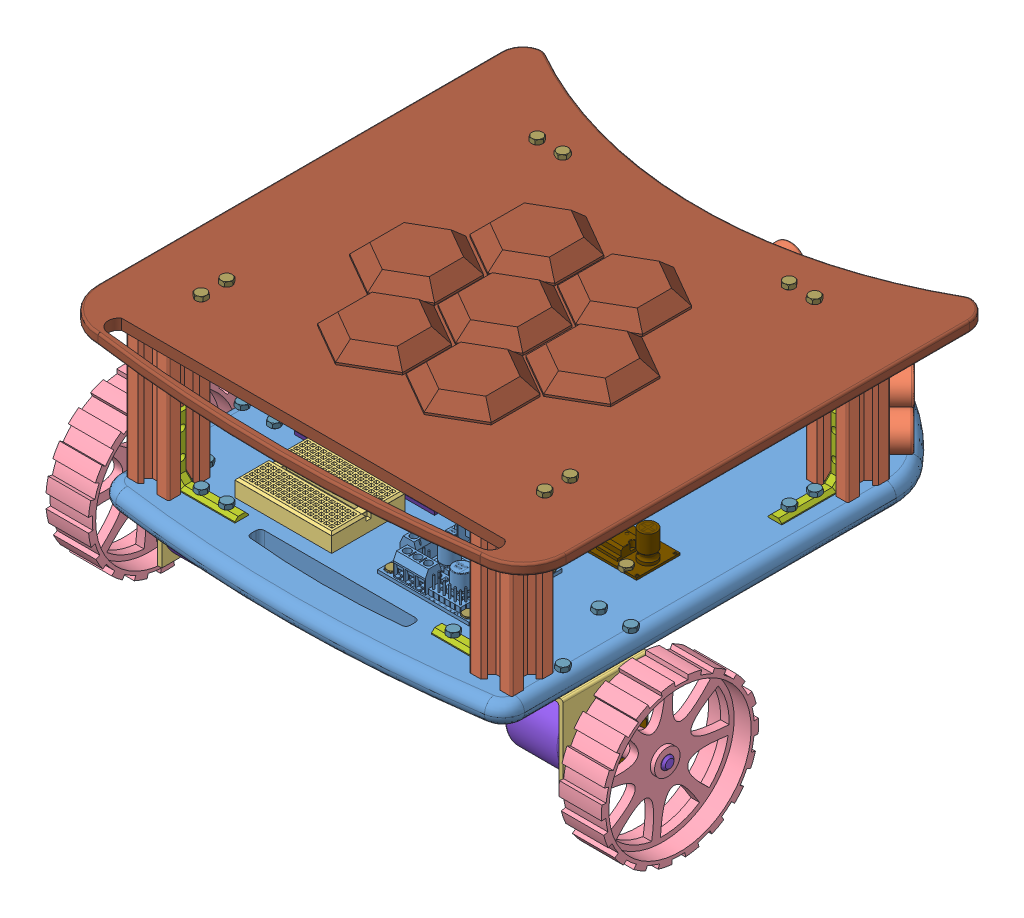
SolidWorks assembly Final_assemb, configuration Default. Lengths in mm.
Overall size (260.12 153.89 257.15).
106 component instances, 21 part files, 114 mates.
Components (placement in the parent):
- Base-1: Base [Default] at (68.6888 135.2882 259.6068) size (190.39 10 252.17)
- aluminium profile-4: aluminium profile [Default] at (-11.2641 145.2882 319.0712) size (20 60 20)
- aluminium profile-5: aluminium profile [Default] at (-12.0261 145.2882 160.7088) size (20 60 20)
- aluminium profile-6: aluminium profile [Default] at (149.3096 145.2882 318.1148) size (20 60 20)
- aluminium profile-7: aluminium profile [Default] at (149.3897 145.2882 159.9163) size (20 60 20)
- motor_mount-1: motor_mount [Default] at (-26.6342 116.2882 288.9148) x (-0.000001 0 -1) z (1 0 -0.000001) size (40 40 23)
- motor_mount-3: motor_mount [Default] at (163.7533 116.2882 288.4009) x (0 0 1) z (-1 0 0) size (40 40 23)
- wheel-1: wheel [Default] at (188.5877 115.3205 288.1355) x (0 0.778001 0.628264) z (-1 0 0) size (73.72 74 22)
- caster wheel.STEP-2: caster wheel.STEP [Default] at (69.4401 93.2882 114.6731) x (-1 0 0) z (0 0 1) size (47 18.41 32)
  - Wheel''s Body.STEP-1: Wheel''s Body.STEP [Default] at origin size (47 8.6 32)
  - Ball.STEP-1: Ball.STEP [Default] at (0 8.6 0) x (0.870425 -0.365315 -0.330008) z (0.347375 -0.019238 0.937529) size (14 14 14)
- L-Bracket-1: L-Bracket [Default] at (-15.1969 145.2882 165.2088) x (0 -1 0) z (1 0 0) size (30 30 6.4)
- L-Bracket-2: L-Bracket [Default] at (146.3725 145.2882 164.4163) x (0 -1 0) z (1 0 0) size (30 30 6.4)
- L-Bracket-4: L-Bracket [Default] at (-6.7641 145.2882 315.9945) x (-1 0 0) z (0 0 1) size (30 30 6.4)
- L-Bracket-5: L-Bracket [Default] at (144.8096 145.2882 321.373) x (1 0 0) z (0 0 -1) size (30 30 6.4)
- dc_motor-1: dc_motor [Default] at (-60.8289 75.9831 269.4134) x (0 0.786629 -0.617426) z (1 0 -0.000001) size (40 40 81)
- dc_motor-2: dc_motor [Default] at (197.948 90.2022 252.8429) x (0 -0.509451 0.8605) z (-1 0 0) size (40 40 81)
- Nut-1: Nut [Default] at (-61.8289 74.5197 307.0863) x (-0.000001 0 -1) z (1 0 -0.000001) size (25.4 22 8)
- Nut-2: Nut [Default] at (136.5586 75.5781 305.943) x (0 0 -1) z (1 0 0) size (25.4 22 8)
- wheel-3: wheel [Default] at (-51.5365 114.3396 289.6726) x (-0.000001 0.009349 -0.999956) z (1 0 -0.000001) size (73.72 74 22)
- castor_support-1: castor_support [Default] at (69.4434 135.2882 114.5913) x (1 0 0) z (0 -1 0) size (54.97 14.97 42)
- L-Bracket-8: L-Bracket [Default] at (-14.8578 205.2882 314.5712) x (0 1 0) z (1 0 0) size (30 30 6.4)
- L-Bracket-9: L-Bracket [Default] at (146.0004 205.2882 313.6148) x (0 1 0) z (1 0 0) size (30 30 6.4)
- L-Bracket-10: L-Bracket [Default] at (-7.5261 205.2882 157.2434) x (0 1 0) z (0 0 1) size (30 30 6.4)
- L-Bracket-11: L-Bracket [Default] at (144.8897 205.2882 156.8646) size (30 30 6.4)
- top plate-4: top plate [Default] at (106.9976 210.2882 168.2291) x (-1 0 0) z (0 -1 0) size (220.27 226.12 12)
- Bolt_assem-2: Bolt_assem [Default] at (121.8897 211.4132 160.0646) x (0.65455 0 0.756019) z (0 -1 0) size (6.35 5 13.28)
- Bolt_assem-3: Bolt_assem [Default] at (15.6675 211.4132 160.4434) x (0.759249 0 -0.650801) z (0 -1 0) size (6.35 5 13.28)
- Bolt_assem-4: Bolt_assem [Default] at (149.2004 211.4132 290.4211) x (1 0 0) z (0 -1 0) size (6.35 5 13.28)
- Bolt_assem-5: Bolt_assem [Default] at (-11.6578 211.4132 303.3776) x (0.046761 0 -0.998906) z (0 -1 0) size (6.35 5 13.28)
- Bolt_assem-6: Bolt_assem [Default] at (-11.6578 211.4132 291.3776) x (1 0 0) z (0 -1 0) size (6.35 5 13.28)
- Bolt_assem-7: Bolt_assem [Default] at (149.2004 211.4132 302.4211) x (1 0 0) z (0 -1 0) size (6.35 5 13.28)
- Bolt_assem-8: Bolt_assem [Default] at (3.6675 211.5814 160.4434) x (1 0 0) z (0 -1 0) size (6.35 5 13.28)
- Bolt_assem-9: Bolt_assem [Default] at (133.8897 211.4132 160.0646) x (1 0 0) z (0 -1 0) size (6.35 5 13.28)
- Nut_assem-1: Nut_assem [Default] at (3.5037 202.2882 160.0608) x (0 0 1) z (0 1 0) size (6.35 5 2.32)
- Nut_assem-2: Nut_assem [Default] at (149.6084 202.2882 290.2996) x (0 0 1) z (0 1 0) size (6.35 5 2.32)
- Nut_assem-3: Nut_assem [Default] at (-11.411 202.2882 291.3133) x (-0.999814 0 -0.019286) z (0 1 0) size (6.35 5 2.32)
- Nut_assem-4: Nut_assem [Default] at (121.6601 202.2882 159.3487) x (0 0 1) z (0 1 0) size (6.35 5 2.32)
- Nut_assem-5: Nut_assem [Default] at (149.4553 202.2882 302.2925) x (0 0 1) z (0 1 0) size (6.35 5 2.32)
- Nut_assem-6: Nut_assem [Default] at (133.8993 202.2882 160.3544) x (0 0 1) z (0 1 0) size (6.35 5 2.32)
- Nut_assem-7: Nut_assem [Default] at (15.634 202.2882 160.571) x (0 0 1) z (0 1 0) size (6.35 5 2.32)
- Nut_assem-8: Nut_assem [Default] at (-12.522 202.2882 303.4842) x (0 0 1) z (0 1 0) size (6.35 5 2.32)
- Bolt_assem_long-1: Bolt_assem_long [Default] at (149.5725 148.4132 187.6099) x (0.999999 0 0.001045) z (0 -1 0) size (6.35 5 17.3)
- Bolt_assem_long-6: Bolt_assem_long [Default] at (149.5725 148.4132 175.6099) x (0.837169 0 -0.546944) z (0 -1 0) size (6.35 5 17.3)
- Bolt_assem_long-7: Bolt_assem_long [Default] at (-11.9969 148.4132 188.4025) x (1 0 0) z (0 -1 0) size (6.35 5 17.3)
- Bolt_assem_long-8: Bolt_assem_long [Default] at (-11.9969 148.4132 176.4025) x (0.837169 0 -0.546944) z (0 -1 0) size (6.35 5 17.3)
- Bolt_assem_long-9: Bolt_assem_long [Default] at (16.2359 148.4132 319.1945) x (1 0 0) z (0 -1 0) size (6.35 5 17.3)
- Bolt_assem_long-10: Bolt_assem_long [Default] at (4.2359 148.4132 319.1945) x (1 0 0) z (0 -1 0) size (6.35 5 17.3)
- Bolt_assem_long-11: Bolt_assem_long [Default] at (121.8096 148.4132 318.173) x (1 0 0) z (0 -1 0) size (6.35 5 17.3)
- Bolt_assem_long-12: Bolt_assem_long [Default] at (133.8096 148.4132 318.173) x (1 0 0) z (0 -1 0) size (6.35 5 17.3)
- Nut_assem-9: Nut_assem [Default] at (-12.0509 134.2882 176.3346) x (0 0 -1) z (0 -1 0) size (6.35 5 2.32)
- Nut_assem-11: Nut_assem [Default] at (-11.9722 134.2882 188.4912) x (0.546944 0 -0.837169) z (0 1 0) size (6.35 5 2.32)
- Nut_assem-12: Nut_assem [Default] at (133.7571 134.2882 318.1542) x (0 0 -1) z (0 -1 0) size (6.35 5 2.32)
- Nut_assem-14: Nut_assem [Default] at (121.9096 134.2882 318.1945) x (0.546944 0 -0.837169) z (0 1 0) size (6.35 5 2.32)
- Nut_assem-16: Nut_assem [Default] at (149.6038 134.2882 187.5825) x (0 0 -1) z (0 -1 0) size (6.35 5 2.32)
- Nut_assem-17: Nut_assem [Default] at (149.5894 134.2882 175.614) x (0 0 -1) z (0 -1 0) size (6.35 5 2.32)
- Nut_assem-18: Nut_assem [Default] at (4.2566 134.2882 319.1949) x (0 0 -1) z (0 -1 0) size (6.35 5 2.32)
- Nut_assem-19: Nut_assem [Default] at (16.166 134.2882 319.1223) x (0 0 -1) z (0 -1 0) size (6.35 5 2.32)
- Bolt_assem_long-13: Bolt_assem_long [Default] at (-22.6342 146.4132 272.9148) x (1 0 0) z (0 -1 0) size (6.35 5 17.3)
- Bolt_assem_long-14: Bolt_assem_long [Default] at (-22.6342 146.4132 304.8928) x (1 0 0) z (0 -1 0) size (6.35 5 17.3)
- Bolt_assem_long-15: Bolt_assem_long [Default] at (144.7334 146.4132 304.3609) x (1 0 0) z (0 -1 0) size (6.35 5 17.3)
- Bolt_assem_long-16: Bolt_assem_long [Default] at (159.7533 146.4132 272.3947) x (1 0 0) z (0 -1 0) size (6.35 5 17.3)
- Bolt_assem_long-17: Bolt_assem_long [Default] at (-7.6315 146.4132 304.8928) x (1 0 0) z (0 -1 0) size (6.35 5 17.3)
- Bolt_assem_long-19: Bolt_assem_long [Default] at (144.7334 146.4132 272.3947) x (1 0 0) z (0 -1 0) size (6.35 5 17.3)
- Bolt_assem_long-20: Bolt_assem_long [Default] at (159.7533 146.4132 304.4246) x (1 0 0) z (0 -1 0) size (6.35 5 17.3)
- Nut_assem-20: Nut_assem [Default] at (-22.5393 133.2882 304.6171) x (1 0 0) z (0 -1 0) size (6.35 5 2.32)
- Nut_assem-21: Nut_assem [Default] at (159.8276 133.2882 304.0619) x (1 0 0) z (0 -1 0) size (6.35 5 2.32)
- Nut_assem-22: Nut_assem [Default] at (144.8243 133.2882 304.6251) x (1 0 0) z (0 -1 0) size (6.35 5 2.32)
- Nut_assem-23: Nut_assem [Default] at (144.7543 133.2882 272.6567) x (1 0 0) z (0 -1 0) size (6.35 5 2.32)
- Nut_assem-24: Nut_assem [Default] at (-7.6221 133.2882 272.6779) x (1 0 0) z (0 -1 0) size (6.35 5 2.32)
- Nut_assem-25: Nut_assem [Default] at (159.6991 133.2882 272.4232) x (1 0 0) z (0 -1 0) size (6.35 5 2.32)
- Nut_assem-26: Nut_assem [Default] at (-22.6446 133.2882 272.9676) x (1 0 0) z (0 -1 0) size (6.35 5 2.32)
- Nut_assem-27: Nut_assem [Default] at (-7.6901 133.2882 304.4182) x (1 0 0) z (0 -1 0) size (6.35 5 2.32)
- castor_bolt-1: castor_bolt [Default] at (49.4434 146.4132 114.5913) x (1 0 0) z (0 -1 0) size (6.35 5 59.25)
- castor_bolt-2: castor_bolt [Default] at (89.4434 146.159 114.5913) x (1 0 0) z (0 -1 0) size (6.35 5 59.25)
- Nut_assem-28: Nut_assem [Default] at (49.5162 91.6882 114.5621) x (1 0 0) z (0 -1 0) size (6.35 5 2.32)
- Nut_assem-29: Nut_assem [Default] at (89.4361 91.6882 114.6274) x (1 0 0) z (0 -1 0) size (6.35 5 2.32)
- Bolt_assem_long-36: Bolt_assem_long [Default] at (-7.6152 146.4132 272.7898) x (1 0 0) z (0 -1 0) size (6.35 5 17.3)
- battery-2: battery [Default] at (86.5307 145.2882 146.2454) x (0 0 -1) z (1 0 0) size (54.67 25 165.5)
- arduino-3: arduino [Défaut] at (1.1947 145.2882 272.2556) x (1 0 0) z (0 1 0) size (75 53.3 12.5)
- buck convertor-2: buck convertor [Default] at (349.4183 145.2882 335.9208) x (1 0 0) z (0 1 0) size (43.52 20.5 14.03)
- p_L298N-3: p_L298N [Predeterminado] at (77.3293 145.2882 309.241) size (43 29.51 43.75)
- Bolt_assem-13: Bolt_assem [Default] at (66.9021 146.4132 236.6396) x (1 0 0) z (0 -1 0) size (6.35 5 13.28)
- Bolt_assem-14: Bolt_assem [Default] at (66.9575 146.4132 264.8847) x (1 0 0) z (0 -1 0) size (6.35 5 13.28)
- Bolt_assem-15: Bolt_assem [Default] at (80.201 146.4132 269.1016) x (1 0 0) z (0 -1 0) size (6.35 5 13.28)
- Bolt_assem-16: Bolt_assem [Default] at (80.4527 146.4132 305.3398) x (1 0 0) z (0 -1 0) size (6.35 5 13.28)
- Bolt_assem-17: Bolt_assem [Default] at (117.0401 146.4132 306.0893) x (1 0 0) z (0 -1 0) size (6.35 5 13.28)
- Bolt_assem-18: Bolt_assem [Default] at (15.0173 146.4132 269.3819) x (1 0 0) z (0 -1 0) size (6.35 5 13.28)
- Bolt_assem-19: Bolt_assem [Default] at (104.5839 146.4132 233.0821) x (1 0 0) z (0 -1 0) size (6.35 5 13.28)
- Bolt_assem-20: Bolt_assem [Default] at (16.2381 146.4132 221.8585) x (1 0 0) z (0 -1 0) size (6.35 5 13.28)
- Bolt_assem-21: Bolt_assem [Default] at (117.3137 146.4132 268.5476) x (1 0 0) z (0 -1 0) size (6.35 5 13.28)
- Bolt_assem-22: Bolt_assem [Default] at (134.1003 146.4132 248.9091) x (1 0 0) z (0 -1 0) size (6.35 5 13.28)
- Ultrasonidos-6: Ultrasonidos [Predeterminado] at (70.3827 155.4882 107.0797) x (1 0 0) z (0 1 0) size (45.4 16.85 26.9)
- Ultrasonidos-7: Ultrasonidos [Predeterminado] at (1.9972 155.4882 133.0682) x (0.758421 0 -0.651766) z (0 1 0) size (45.4 16.85 26.9)
- Ultrasonidos-8: Ultrasonidos [Predeterminado] at (137.5185 155.4882 134.5641) x (0.703507 0 0.710688) z (0 1 0) size (45.4 16.85 26.9)
- Nut_assem-31: Nut_assem [Default] at (104.8675 134.2882 233.3294) x (1 0 0) z (0 -1 0) size (6.35 5 2.32)
- Nut_assem-33: Nut_assem [Default] at (66.8991 134.2882 264.7931) x (1 0 0) z (0 -1 0) size (6.35 5 2.32)
- Nut_assem-34: Nut_assem [Default] at (116.8498 134.2882 306.8069) x (1 0 0) z (0 -1 0) size (6.35 5 2.32)
- Nut_assem-35: Nut_assem [Default] at (16.1628 134.2882 221.8829) x (1 0 0) z (0 -1 0) size (6.35 5 2.32)
- Nut_assem-36: Nut_assem [Default] at (66.8813 134.2882 236.6974) x (1 0 0) z (0 -1 0) size (6.35 5 2.32)
- Nut_assem-37: Nut_assem [Default] at (134.1867 134.2882 248.9418) x (1 0 0) z (0 -1 0) size (6.35 5 2.32)
- Nut_assem-38: Nut_assem [Default] at (80.3983 134.2882 305.7162) x (1 0 0) z (0 -1 0) size (6.35 5 2.32)
- Nut_assem-39: Nut_assem [Default] at (80.0758 134.2882 269.0192) x (1 0 0) z (0 -1 0) size (6.35 5 2.32)
- Nut_assem-40: Nut_assem [Default] at (117.3236 134.2882 268.0356) x (1 0 0) z (0 -1 0) size (6.35 5 2.32)
- Nut_assem-41: Nut_assem [Default] at (14.9868 134.2882 269.1268) x (1 0 0) z (0 -1 0) size (6.35 5 2.32)
- MiniBreadboard-1: MiniBreadboard [Default] at (35.6153 145.2882 294.6806) x (0 0 1) z (-1 0 0) size (34.6 8.15 45.6)
Mates (geometry in assembly coordinates):
- Lock5: lock: unknown of Base-1; unknown of aluminium profile-7
- Lock6: lock: unknown of Base-1; unknown of aluminium profile-5
- Lock9: lock: unknown of Base-1; unknown of aluminium profile-4
- Lock10: lock: unknown of Base-1; unknown of aluminium profile-6
- Lock15: lock: unknown of Base-1; unknown of motor_mount-3
- Lock16: lock: unknown of Base-1; unknown of motor_mount-1
- Lock26: lock: unknown of Base-1; unknown of L-Bracket-1
- Lock27: lock: unknown of aluminium profile-5; unknown of L-Bracket-1
- Lock28: lock: unknown of aluminium profile-7; unknown of L-Bracket-2
- Lock29: lock: unknown of Base-1; unknown of L-Bracket-2
- Lock97: lock: unknown of Base-1; unknown of L-Bracket-4
- Lock98: lock: unknown of aluminium profile-4; unknown of L-Bracket-4
- Lock99: lock: unknown of aluminium profile-6; unknown of L-Bracket-5
- Lock96: lock: unknown of Base-1; unknown of L-Bracket-5
- Lock32: lock: unknown of motor_mount-1; unknown of dc_motor-1
- Lock30: lock: unknown of motor_mount-1; unknown of dc_motor-1
- Lock31: lock: unknown of motor_mount-1; unknown of Nut-1
- Lock33: lock: unknown of motor_mount-3; unknown of dc_motor-2
- Lock34: lock: unknown of Base-1; unknown of dc_motor-2
- Lock35: lock: unknown of motor_mount-3; unknown of Nut-2
- Lock36: lock: unknown of wheel_v2-1; unknown of dc_motor-2
- Lock37: lock: unknown of dc_motor-1; unknown of wheel_v2-3
- Lock38: lock: unknown of Base-1; unknown of castor_support-1
- Lock39: lock: unknown of caster wheel.STEP-2/Wheel''s Body.STEP-1; unknown of castor_support-1
- Lock51: lock: unknown of aluminium profile-7; unknown of L-Bracket-11
- Lock50: lock: unknown of aluminium profile-5; unknown of L-Bracket-10
- Lock49: lock: unknown of aluminium profile-4; unknown of L-Bracket-8
- Lock48: lock: unknown of aluminium profile-6; unknown of L-Bracket-9
- Lock47: lock: unknown of aluminium profile-7; unknown of top plate-4
- Lock46: lock: unknown of L-Bracket-11; unknown of top plate-4
- Lock45: lock: unknown of L-Bracket-10; unknown of top plate-4
- Lock44: lock: unknown of aluminium profile-5; unknown of top plate-4
- Lock43: lock: unknown of L-Bracket-8; unknown of top plate-4
- Lock42: lock: unknown of aluminium profile-4; unknown of top plate-4
- Lock41: lock: unknown of L-Bracket-9; unknown of top plate-4
- Lock40: lock: unknown of aluminium profile-6; unknown of top plate-4
- Coincident104: coincident anti-aligned: circle of top plate-4; plane of Bolt_assem-5 through (-11.6578 210.2882 303.3776) normal (0 -1 0)
- Coincident105: coincident anti-aligned: circle of top plate-4; circle of Bolt_assem-6
- Coincident108: coincident anti-aligned: circle of top plate-4; circle of Bolt_assem-7
- Coincident107: coincident anti-aligned: circle of top plate-4; circle of Bolt_assem-4
- Coincident109: coincident anti-aligned: circle of top plate-4; circle of Bolt_assem-3
- Coincident111: coincident anti-aligned: circle of top plate-4; circle of Bolt_assem-2
- Coincident112: coincident anti-aligned: plane of Nut_assem-2 through (149.6084 203.2882 290.2996) normal (0 1 0); plane of L-Bracket-9 through (152.4004 203.2882 308.7864) normal (0 -1 0)
- Lock52: lock: unknown of L-Bracket-8; unknown of Nut_assem-3
- Lock53: lock: unknown of L-Bracket-8; unknown of Nut_assem-8
- Lock54: lock: unknown of L-Bracket-9; unknown of Nut_assem-5
- Lock55: lock: unknown of L-Bracket-11; unknown of Nut_assem-6
- Lock56: lock: unknown of L-Bracket-11; unknown of Nut_assem-4
- Lock57: lock: unknown of L-Bracket-10; unknown of Nut_assem-1
- Lock58: lock: unknown of L-Bracket-10; unknown of Nut_assem-7
- Coincident126: coincident anti-aligned: circle of L-Bracket-2; circle of Bolt_assem_long-6
- Coincident127: coincident anti-aligned: circle of L-Bracket-1; circle of Bolt_assem_long-8
- Coincident128: coincident anti-aligned: circle of L-Bracket-1; circle of Bolt_assem_long-7
- Coincident129: coincident anti-aligned: circle of L-Bracket-2; circle of Bolt_assem_long-1
- Coincident131: coincident anti-aligned: circle of L-Bracket-5; circle of Bolt_assem_long-12
- Coincident132: coincident anti-aligned: circle of L-Bracket-5; circle of Bolt_assem_long-11
- Coincident133: coincident anti-aligned: circle of L-Bracket-4; circle of Bolt_assem_long-10
- Coincident134: coincident anti-aligned: circle of L-Bracket-4; circle of Bolt_assem_long-9
- Lock65: lock: unknown of Base-1; unknown of Nut_assem-9
- Lock64: lock: unknown of Base-1; unknown of Nut_assem-11
- Lock61: lock: unknown of Base-1; unknown of Nut_assem-12
- Lock59: lock: unknown of Base-1; unknown of Nut_assem-14
- Lock60: lock: unknown of Base-1; unknown of Nut_assem-16
- Lock108: lock: unknown of Base-1; unknown of Nut_assem-17
- Lock109: lock: unknown of Base-1; unknown of Nut_assem-18
- Lock110: lock: unknown of Base-1; unknown of Nut_assem-19
- Coincident1482: coincident aligned: circle of Base-1; circle of Bolt_assem_long-14
- Coincident1483: coincident aligned: circle of Base-1; circle of Bolt_assem_long-13
- Coincident1485: coincident aligned: circle of Base-1; circle of Bolt_assem_long-20
- Coincident1486: coincident aligned: circle of Base-1; circle of Bolt_assem_long-16
- Coincident1487: coincident aligned: circle of Base-1; circle of Bolt_assem_long-17
- Coincident1488: coincident aligned: circle of Base-1; circle of Bolt_assem_long-15
- Coincident1489: coincident aligned: circle of Base-1; circle of Bolt_assem_long-19
- Lock68: lock: unknown of motor_mount-3; unknown of Nut_assem-25
- Lock67: lock: unknown of motor_mount-3; unknown of Nut_assem-21
- Lock66: lock: unknown of motor_mount-3; unknown of Nut_assem-22
- Lock72: lock: unknown of motor_mount-3; unknown of Nut_assem-23
- Lock70: lock: unknown of motor_mount-1; unknown of Nut_assem-20
- Lock71: lock: unknown of motor_mount-1; unknown of Nut_assem-24
- Lock73: lock: unknown of motor_mount-1; unknown of Nut_assem-26
- Lock69: lock: unknown of motor_mount-1; unknown of Nut_assem-27
- Coincident1497: coincident anti-aligned: circle of Base-1; circle of castor_bolt-1
- Concentric3: concentric anti-aligned: circle of Base-1; circle of castor_bolt-2
- Lock75: lock: unknown of caster wheel.STEP-2/Wheel''s Body.STEP-1; unknown of Nut_assem-28
- Lock74: lock: unknown of caster wheel.STEP-2/Wheel''s Body.STEP-1; unknown of Nut_assem-29
- Lock112: lock: unknown of Base-1; unknown of Bolt_assem_long-36
- Lock113: lock: unknown of Base-1; unknown of battery-2
- Lock114: lock: unknown of Base-1; unknown of buck convertor-2
- Lock116: lock: unknown of Base-1; unknown of arduino-3
- Lock115: lock: unknown of Base-1; unknown of p_L298N_V2-3
- Lock137: lock: unknown of Base-1; unknown of Bolt_assem-17
- Lock138: lock: unknown of Base-1; unknown of Bolt_assem-21
- Lock135: lock: unknown of Base-1; unknown of Bolt_assem-22
- Lock136: lock: unknown of Base-1; unknown of Bolt_assem-20
- Lock133: lock: unknown of Base-1; unknown of Bolt_assem-19
- Lock134: lock: unknown of Base-1; unknown of Bolt_assem-14
- Lock132: lock: unknown of Base-1; unknown of Bolt_assem-16
- Lock131: lock: unknown of Base-1; unknown of Bolt_assem-18
- Lock130: lock: unknown of Base-1; unknown of Bolt_assem-15
- Lock129: lock: unknown of Base-1; unknown of Bolt_assem-13
- Lock127: lock: unknown of Base-1; unknown of Ultrasonidos-6
- Lock128: lock: unknown of Base-1; unknown of Ultrasonidos-7
- Lock126: lock: unknown of Base-1; unknown of Ultrasonidos-8
- Coincident1526: coincident anti-aligned: plane of Base-1 through (153.5085 135.2882 326.5) normal (0 -1 0); plane of Nut_assem-38 through (80.3983 135.2882 305.7162) normal (0 1 0)
- Lock125: lock: unknown of Base-1; unknown of Nut_assem-35
- Lock124: lock: unknown of Base-1; unknown of Nut_assem-34
- Lock123: lock: unknown of Base-1; unknown of Nut_assem-31
- Lock122: lock: unknown of Base-1; unknown of Nut_assem-33
- Lock121: lock: unknown of Base-1; unknown of Nut_assem-37
- Lock120: lock: unknown of Base-1; unknown of Nut_assem-36
- Lock119: lock: unknown of Base-1; unknown of Nut_assem-39
- Lock117: lock: unknown of Base-1; unknown of Nut_assem-40
- Lock118: lock: unknown of Base-1; unknown of Nut_assem-41
- Lock139: lock: unknown of Base-1; unknown of MiniBreadboard-1
